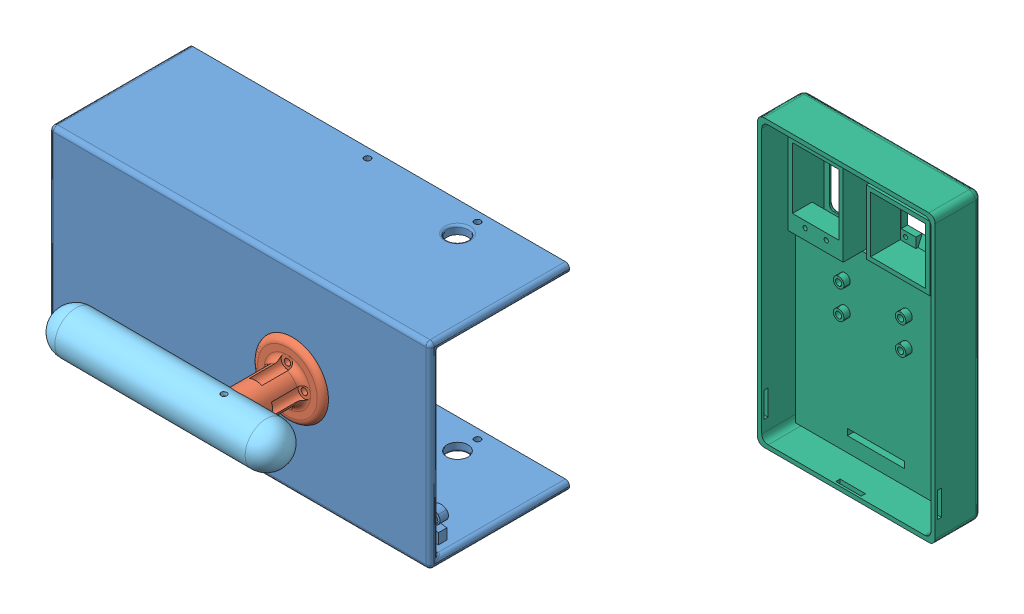
SolidWorks assembly 装配体, configuration 默认. Lengths in mm.
Overall size (296.84 142.87 186.43).
8 component instances, 8 part files, 18 mates.
Components (placement in the parent):
- 外壳-2: 外壳 [默认] at (-255.025 -26.9479 406.6556) x (0 -1 0) z (1 0 0) size (93 66 180)
- 把手-2: 把手 [默认] at (24.2887 4.5521 465.5397) x (0.003824 0.999993 0) z (0 0 1) size (34 34 41.4)
- 连接件-1: 连接件 [默认] at (23.1149 4.5566 460.5397) x (0.999993 -0.003824 0) z (0 0 1) size (42.97 36.78 30)
- 标准舵机-1: 标准舵机 [默认] at (-47.8119 17.6106 407.8397) x (-1 0 0) z (0 1 0) (suppressed, hidden)
- 舵机盘-1: 舵机盘 [默认] at (-36.4113 17.6106 456.7397) x (0.951733 -0.306928 0) z (0.306928 0.951733 0) (suppressed, hidden)
- 转盘-1: 转盘 [默认] at (-36.4113 17.6106 456.7397) x (0.306928 0.951733 0) z (0 0 1) size (30 30 9)
- 把手2-1: 把手2 [默认] at (54.2885 4.4374 501.9397) x (0.003824 0.999993 0) z (0 0 1) size (20 110 20)
- 门外 - 副本-1: 门外 - 副本 [默认] at (164.1239 33.4251 327.5231) x (-1 0 0) z (0 0 -1) size (84 135 22.01)
Mates (geometry in assembly coordinates):
- 同心6: concentric aligned: cylinder of 外壳-2 through (24.2887 4.5521 403.5387) axis (0 0 1) radius 10; cylinder of 把手-2 through (24.2887 4.5521 465.5397) axis (0 0 1) radius 9.8
- 重合2: coincident anti-aligned: plane of 外壳-2 through (89.2887 -41.9479 469.5397) normal (0 0 1); plane of 把手-2 through (24.2887 4.5521 469.5397) normal (0 0 -1)
- 重合4: coincident anti-aligned: plane of 把手-2 through (24.2887 4.5521 461.5397) normal (0 0 -1); plane of 连接件-1 through (24.2887 4.5521 461.5397) normal (0 0 1)
- 同心7: concentric anti-aligned: circle of 把手-2; cylinder of 连接件-1 through (32.3465 12.494 463.5397) axis (0 0 1) radius 1.55
- 重合7: coincident anti-aligned: plane of 外壳-2 through (-255.025 -26.9479 440.5397) normal (0 0 -1); plane of 标准舵机-1 through (-19.4113 7.0521 440.5397) normal (0 0 1)
- 同心8: concentric anti-aligned: circle of 外壳-2; circle of 标准舵机-1
- 同心9: concentric anti-aligned: circle of 外壳-2; circle of 标准舵机-1
- 同心10: concentric aligned: cylinder of 标准舵机-1 through (-36.4113 17.6106 455.2397) axis (0 0 -1) radius 3; cylinder of 舵机盘-1 through (-36.4113 17.6106 455.2397) axis (0 0 -1) radius 3
- 重合8: coincident anti-aligned: plane of 标准舵机-1 through (-36.4113 17.6106 455.2397) normal (0 0 1); plane of 舵机盘-1 through (-36.4113 17.6106 455.2397) normal (0 0 -1)
- 同心11: concentric aligned: circle of 舵机盘-1; circle of 转盘-1
- 同心12: concentric aligned: circle of 舵机盘-1; circle of 转盘-1
- 重合9: coincident anti-aligned: plane of 舵机盘-1 through (-36.4113 17.6106 456.7397) normal (0 0 1); plane of 转盘-1 through (-36.4113 17.6106 456.7397) normal (0 0 -1)
- 同心13: concentric aligned: circle of 连接件-1; circle of 上拉杆-1
- 重合10: coincident anti-aligned: plane of 连接件-1 through (23.1149 4.5566 460.5397) normal (0 0 1); plane of 上拉杆-1 through (60.4799 15.7632 460.5397) normal (0 0 -1)
- 同心14: concentric aligned: circle of 转盘-1; circle of 上拉杆-1
- 重合11: coincident aligned: plane of 把手-2 through (39.0886 4.4955 469.5397) normal (-0.003824 -0.999993 0); plane of 连接件-1 through (37.6248 4.5011 465.5397) normal (-0.003824 -0.999993 0)
- 同心15: concentric aligned: circle of 把手-2; circle of 把手2-1
- 同心16: concentric aligned: cylinder of 把手-2 through (24.2237 -12.4487 501.9397) axis (0.003824 0.999993 0) radius 1.5; cylinder of 把手2-1 through (24.2505 -5.4478 501.9397) axis (0.003824 0.999993 0) radius 1.4
